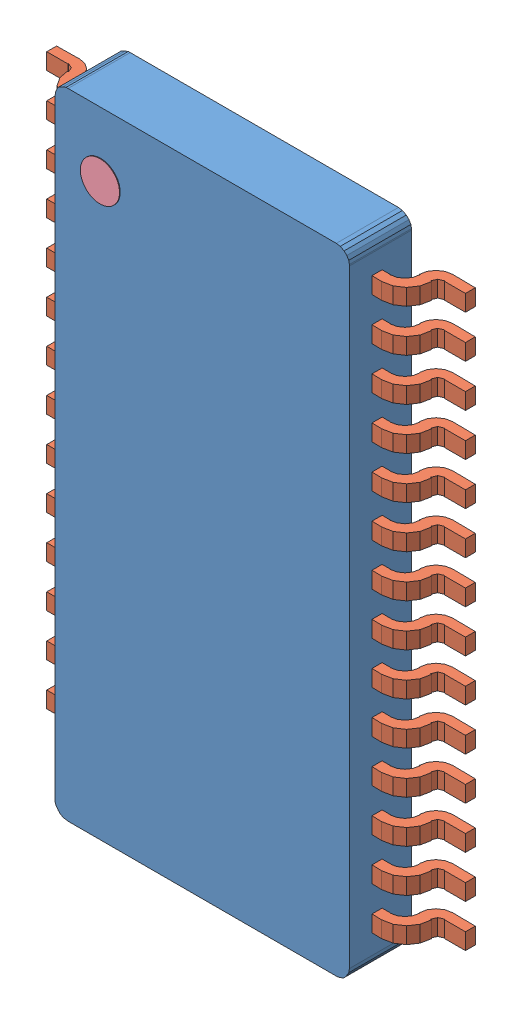
SolidWorks assembly User Library-TSSOP-28_P065, configuration Default. Lengths in mm.
Overall size (6.4 9.7 0.99).
146 component instances, 5 part files, 0 mates.
Components (placement in the parent):
- User Library-TSSOP-28_P065_Free-Models2-1: User Library-TSSOP-28_P065_Free-Models2 [Default] at origin size (6.4 9.7 0.99)
  - User Library-TSSOP-28_P065_455332561-1: User Library-TSSOP-28_P065_455332561 [Default] at (0 0 -0.4373) size (4.5 9.7 0.95)
    - User Library-TSSOP-28_P065_Extruded2-1: User Library-TSSOP-28_P065_Extruded2 [Default] at origin size (4.5 9.7 0.95)
  - User Library-TSSOP-28_P065_PINTSSOP-57-1: User Library-TSSOP-28_P065_PINTSSOP-57 [Default] at (2.1 0.4373 0.0127) x (-1 0 0) z (0 1 0) size (1.1 0.64 0.42)
    - User Library-TSSOP-28_P065_Free-Models3-1: User Library-TSSOP-28_P065_Free-Models3 [Default] at origin size (1.1 0.64 0.25)
      - User Library-TSSOP-28_P065_353885137-1: User Library-TSSOP-28_P065_353885137 [Default] at (-0.55 -0.1603 -0.2373) size (1.1 0.64 0.25)
        - User Library-TSSOP-28_P065_Extruded3-1: User Library-TSSOP-28_P065_Extruded3 [Default] at origin size (1.1 0.64 0.25)
    - User Library-TSSOP-28_P065_Board3-1: User Library-TSSOP-28_P065_Board3 [Default] at (0 0 -0.4039) size (0 0 0.42)
  - User Library-TSSOP-28_P065_PINTSSOP-57-2: User Library-TSSOP-28_P065_PINTSSOP-57 [Default] at (-2.1 0.8627 0.0127) x (1 0 0) z (0 -1 0) size (1.1 0.64 0.42)
    - User Library-TSSOP-28_P065_Free-Models3-1: User Library-TSSOP-28_P065_Free-Models3 [Default] at origin size (1.1 0.64 0.25)
      - User Library-TSSOP-28_P065_353885137-1: User Library-TSSOP-28_P065_353885137 [Default] at (-0.55 -0.1603 -0.2373) size (1.1 0.64 0.25)
        - User Library-TSSOP-28_P065_Extruded3-1: User Library-TSSOP-28_P065_Extruded3 [Default] at origin size (1.1 0.64 0.25)
    - User Library-TSSOP-28_P065_Board3-1: User Library-TSSOP-28_P065_Board3 [Default] at (0 0 -0.4039) size (0 0 0.42)
  - User Library-TSSOP-28_P065_PINTSSOP-57-3: User Library-TSSOP-28_P065_PINTSSOP-57 [Default] at (2.1 1.0873 0.0127) x (-1 0 0) z (0 1 0) size (1.1 0.64 0.42)
    - User Library-TSSOP-28_P065_Free-Models3-1: User Library-TSSOP-28_P065_Free-Models3 [Default] at origin size (1.1 0.64 0.25)
      - User Library-TSSOP-28_P065_353885137-1: User Library-TSSOP-28_P065_353885137 [Default] at (-0.55 -0.1603 -0.2373) size (1.1 0.64 0.25)
        - User Library-TSSOP-28_P065_Extruded3-1: User Library-TSSOP-28_P065_Extruded3 [Default] at origin size (1.1 0.64 0.25)
    - User Library-TSSOP-28_P065_Board3-1: User Library-TSSOP-28_P065_Board3 [Default] at (0 0 -0.4039) size (0 0 0.42)
  - User Library-TSSOP-28_P065_PINTSSOP-57-4: User Library-TSSOP-28_P065_PINTSSOP-57 [Default] at (-2.1 1.5127 0.0127) x (1 0 0) z (0 -1 0) size (1.1 0.64 0.42)
    - User Library-TSSOP-28_P065_Free-Models3-1: User Library-TSSOP-28_P065_Free-Models3 [Default] at origin size (1.1 0.64 0.25)
      - User Library-TSSOP-28_P065_353885137-1: User Library-TSSOP-28_P065_353885137 [Default] at (-0.55 -0.1603 -0.2373) size (1.1 0.64 0.25)
        - User Library-TSSOP-28_P065_Extruded3-1: User Library-TSSOP-28_P065_Extruded3 [Default] at origin size (1.1 0.64 0.25)
    - User Library-TSSOP-28_P065_Board3-1: User Library-TSSOP-28_P065_Board3 [Default] at (0 0 -0.4039) size (0 0 0.42)
  - User Library-TSSOP-28_P065_PINTSSOP-57-5: User Library-TSSOP-28_P065_PINTSSOP-57 [Default] at (2.1 1.7373 0.0127) x (-1 0 0) z (0 1 0) size (1.1 0.64 0.42)
    - User Library-TSSOP-28_P065_Free-Models3-1: User Library-TSSOP-28_P065_Free-Models3 [Default] at origin size (1.1 0.64 0.25)
      - User Library-TSSOP-28_P065_353885137-1: User Library-TSSOP-28_P065_353885137 [Default] at (-0.55 -0.1603 -0.2373) size (1.1 0.64 0.25)
        - User Library-TSSOP-28_P065_Extruded3-1: User Library-TSSOP-28_P065_Extruded3 [Default] at origin size (1.1 0.64 0.25)
    - User Library-TSSOP-28_P065_Board3-1: User Library-TSSOP-28_P065_Board3 [Default] at (0 0 -0.4039) size (0 0 0.42)
  - User Library-TSSOP-28_P065_PINTSSOP-57-6: User Library-TSSOP-28_P065_PINTSSOP-57 [Default] at (-2.1 2.1627 0.0127) x (1 0 0) z (0 -1 0) size (1.1 0.64 0.42)
    - User Library-TSSOP-28_P065_Free-Models3-1: User Library-TSSOP-28_P065_Free-Models3 [Default] at origin size (1.1 0.64 0.25)
      - User Library-TSSOP-28_P065_353885137-1: User Library-TSSOP-28_P065_353885137 [Default] at (-0.55 -0.1603 -0.2373) size (1.1 0.64 0.25)
        - User Library-TSSOP-28_P065_Extruded3-1: User Library-TSSOP-28_P065_Extruded3 [Default] at origin size (1.1 0.64 0.25)
    - User Library-TSSOP-28_P065_Board3-1: User Library-TSSOP-28_P065_Board3 [Default] at (0 0 -0.4039) size (0 0 0.42)
  - User Library-TSSOP-28_P065_PINTSSOP-57-7: User Library-TSSOP-28_P065_PINTSSOP-57 [Default] at (2.1 2.3873 0.0127) x (-1 0 0) z (0 1 0) size (1.1 0.64 0.42)
    - User Library-TSSOP-28_P065_Free-Models3-1: User Library-TSSOP-28_P065_Free-Models3 [Default] at origin size (1.1 0.64 0.25)
      - User Library-TSSOP-28_P065_353885137-1: User Library-TSSOP-28_P065_353885137 [Default] at (-0.55 -0.1603 -0.2373) size (1.1 0.64 0.25)
        - User Library-TSSOP-28_P065_Extruded3-1: User Library-TSSOP-28_P065_Extruded3 [Default] at origin size (1.1 0.64 0.25)
    - User Library-TSSOP-28_P065_Board3-1: User Library-TSSOP-28_P065_Board3 [Default] at (0 0 -0.4039) size (0 0 0.42)
  - User Library-TSSOP-28_P065_PINTSSOP-57-8: User Library-TSSOP-28_P065_PINTSSOP-57 [Default] at (-2.1 2.8127 0.0127) x (1 0 0) z (0 -1 0) size (1.1 0.64 0.42)
    - User Library-TSSOP-28_P065_Free-Models3-1: User Library-TSSOP-28_P065_Free-Models3 [Default] at origin size (1.1 0.64 0.25)
      - User Library-TSSOP-28_P065_353885137-1: User Library-TSSOP-28_P065_353885137 [Default] at (-0.55 -0.1603 -0.2373) size (1.1 0.64 0.25)
        - User Library-TSSOP-28_P065_Extruded3-1: User Library-TSSOP-28_P065_Extruded3 [Default] at origin size (1.1 0.64 0.25)
    - User Library-TSSOP-28_P065_Board3-1: User Library-TSSOP-28_P065_Board3 [Default] at (0 0 -0.4039) size (0 0 0.42)
  - User Library-TSSOP-28_P065_PINTSSOP-57-9: User Library-TSSOP-28_P065_PINTSSOP-57 [Default] at (2.1 3.0373 0.0127) x (-1 0 0) z (0 1 0) size (1.1 0.64 0.42)
    - User Library-TSSOP-28_P065_Free-Models3-1: User Library-TSSOP-28_P065_Free-Models3 [Default] at origin size (1.1 0.64 0.25)
      - User Library-TSSOP-28_P065_353885137-1: User Library-TSSOP-28_P065_353885137 [Default] at (-0.55 -0.1603 -0.2373) size (1.1 0.64 0.25)
        - User Library-TSSOP-28_P065_Extruded3-1: User Library-TSSOP-28_P065_Extruded3 [Default] at origin size (1.1 0.64 0.25)
    - User Library-TSSOP-28_P065_Board3-1: User Library-TSSOP-28_P065_Board3 [Default] at (0 0 -0.4039) size (0 0 0.42)
  - User Library-TSSOP-28_P065_PINTSSOP-57-10: User Library-TSSOP-28_P065_PINTSSOP-57 [Default] at (-2.1 3.4627 0.0127) x (1 0 0) z (0 -1 0) size (1.1 0.64 0.42)
    - User Library-TSSOP-28_P065_Free-Models3-1: User Library-TSSOP-28_P065_Free-Models3 [Default] at origin size (1.1 0.64 0.25)
      - User Library-TSSOP-28_P065_353885137-1: User Library-TSSOP-28_P065_353885137 [Default] at (-0.55 -0.1603 -0.2373) size (1.1 0.64 0.25)
        - User Library-TSSOP-28_P065_Extruded3-1: User Library-TSSOP-28_P065_Extruded3 [Default] at origin size (1.1 0.64 0.25)
    - User Library-TSSOP-28_P065_Board3-1: User Library-TSSOP-28_P065_Board3 [Default] at (0 0 -0.4039) size (0 0 0.42)
  - User Library-TSSOP-28_P065_PINTSSOP-57-11: User Library-TSSOP-28_P065_PINTSSOP-57 [Default] at (2.1 3.6873 0.0127) x (-1 0 0) z (0 1 0) size (1.1 0.64 0.42)
    - User Library-TSSOP-28_P065_Free-Models3-1: User Library-TSSOP-28_P065_Free-Models3 [Default] at origin size (1.1 0.64 0.25)
      - User Library-TSSOP-28_P065_353885137-1: User Library-TSSOP-28_P065_353885137 [Default] at (-0.55 -0.1603 -0.2373) size (1.1 0.64 0.25)
        - User Library-TSSOP-28_P065_Extruded3-1: User Library-TSSOP-28_P065_Extruded3 [Default] at origin size (1.1 0.64 0.25)
    - User Library-TSSOP-28_P065_Board3-1: User Library-TSSOP-28_P065_Board3 [Default] at (0 0 -0.4039) size (0 0 0.42)
  - User Library-TSSOP-28_P065_PINTSSOP-57-12: User Library-TSSOP-28_P065_PINTSSOP-57 [Default] at (-2.1 4.1127 0.0127) x (1 0 0) z (0 -1 0) size (1.1 0.64 0.42)
    - User Library-TSSOP-28_P065_Free-Models3-1: User Library-TSSOP-28_P065_Free-Models3 [Default] at origin size (1.1 0.64 0.25)
      - User Library-TSSOP-28_P065_353885137-1: User Library-TSSOP-28_P065_353885137 [Default] at (-0.55 -0.1603 -0.2373) size (1.1 0.64 0.25)
        - User Library-TSSOP-28_P065_Extruded3-1: User Library-TSSOP-28_P065_Extruded3 [Default] at origin size (1.1 0.64 0.25)
    - User Library-TSSOP-28_P065_Board3-1: User Library-TSSOP-28_P065_Board3 [Default] at (0 0 -0.4039) size (0 0 0.42)
  - User Library-TSSOP-28_P065_PINTSSOP-57-13: User Library-TSSOP-28_P065_PINTSSOP-57 [Default] at (2.1 4.3373 0.0127) x (-1 0 0) z (0 1 0) size (1.1 0.64 0.42)
    - User Library-TSSOP-28_P065_Free-Models3-1: User Library-TSSOP-28_P065_Free-Models3 [Default] at origin size (1.1 0.64 0.25)
      - User Library-TSSOP-28_P065_353885137-1: User Library-TSSOP-28_P065_353885137 [Default] at (-0.55 -0.1603 -0.2373) size (1.1 0.64 0.25)
        - User Library-TSSOP-28_P065_Extruded3-1: User Library-TSSOP-28_P065_Extruded3 [Default] at origin size (1.1 0.64 0.25)
    - User Library-TSSOP-28_P065_Board3-1: User Library-TSSOP-28_P065_Board3 [Default] at (0 0 -0.4039) size (0 0 0.42)
  - User Library-TSSOP-28_P065_PINTSSOP-57-14: User Library-TSSOP-28_P065_PINTSSOP-57 [Default] at (-2.1 -1.7373 0.0127) x (1 0 0) z (0 -1 0) size (1.1 0.64 0.42)
    - User Library-TSSOP-28_P065_Free-Models3-1: User Library-TSSOP-28_P065_Free-Models3 [Default] at origin size (1.1 0.64 0.25)
      - User Library-TSSOP-28_P065_353885137-1: User Library-TSSOP-28_P065_353885137 [Default] at (-0.55 -0.1603 -0.2373) size (1.1 0.64 0.25)
        - User Library-TSSOP-28_P065_Extruded3-1: User Library-TSSOP-28_P065_Extruded3 [Default] at origin size (1.1 0.64 0.25)
    - User Library-TSSOP-28_P065_Board3-1: User Library-TSSOP-28_P065_Board3 [Default] at (0 0 -0.4039) size (0 0 0.42)
  - User Library-TSSOP-28_P065_PINTSSOP-57-15: User Library-TSSOP-28_P065_PINTSSOP-57 [Default] at (2.1 -1.5127 0.0127) x (-1 0 0) z (0 1 0) size (1.1 0.64 0.42)
    - User Library-TSSOP-28_P065_Free-Models3-1: User Library-TSSOP-28_P065_Free-Models3 [Default] at origin size (1.1 0.64 0.25)
      - User Library-TSSOP-28_P065_353885137-1: User Library-TSSOP-28_P065_353885137 [Default] at (-0.55 -0.1603 -0.2373) size (1.1 0.64 0.25)
        - User Library-TSSOP-28_P065_Extruded3-1: User Library-TSSOP-28_P065_Extruded3 [Default] at origin size (1.1 0.64 0.25)
    - User Library-TSSOP-28_P065_Board3-1: User Library-TSSOP-28_P065_Board3 [Default] at (0 0 -0.4039) size (0 0 0.42)
  - User Library-TSSOP-28_P065_PINTSSOP-57-16: User Library-TSSOP-28_P065_PINTSSOP-57 [Default] at (-2.1 -1.0873 0.0127) x (1 0 0) z (0 -1 0) size (1.1 0.64 0.42)
    - User Library-TSSOP-28_P065_Free-Models3-1: User Library-TSSOP-28_P065_Free-Models3 [Default] at origin size (1.1 0.64 0.25)
      - User Library-TSSOP-28_P065_353885137-1: User Library-TSSOP-28_P065_353885137 [Default] at (-0.55 -0.1603 -0.2373) size (1.1 0.64 0.25)
        - User Library-TSSOP-28_P065_Extruded3-1: User Library-TSSOP-28_P065_Extruded3 [Default] at origin size (1.1 0.64 0.25)
    - User Library-TSSOP-28_P065_Board3-1: User Library-TSSOP-28_P065_Board3 [Default] at (0 0 -0.4039) size (0 0 0.42)
  - User Library-TSSOP-28_P065_PINTSSOP-57-17: User Library-TSSOP-28_P065_PINTSSOP-57 [Default] at (2.1 -0.8627 0.0127) x (-1 0 0) z (0 1 0) size (1.1 0.64 0.42)
    - User Library-TSSOP-28_P065_Free-Models3-1: User Library-TSSOP-28_P065_Free-Models3 [Default] at origin size (1.1 0.64 0.25)
      - User Library-TSSOP-28_P065_353885137-1: User Library-TSSOP-28_P065_353885137 [Default] at (-0.55 -0.1603 -0.2373) size (1.1 0.64 0.25)
        - User Library-TSSOP-28_P065_Extruded3-1: User Library-TSSOP-28_P065_Extruded3 [Default] at origin size (1.1 0.64 0.25)
    - User Library-TSSOP-28_P065_Board3-1: User Library-TSSOP-28_P065_Board3 [Default] at (0 0 -0.4039) size (0 0 0.42)
  - User Library-TSSOP-28_P065_PINTSSOP-57-18: User Library-TSSOP-28_P065_PINTSSOP-57 [Default] at (-2.1 -0.4373 0.0127) x (1 0 0) z (0 -1 0) size (1.1 0.64 0.42)
    - User Library-TSSOP-28_P065_Free-Models3-1: User Library-TSSOP-28_P065_Free-Models3 [Default] at origin size (1.1 0.64 0.25)
      - User Library-TSSOP-28_P065_353885137-1: User Library-TSSOP-28_P065_353885137 [Default] at (-0.55 -0.1603 -0.2373) size (1.1 0.64 0.25)
        - User Library-TSSOP-28_P065_Extruded3-1: User Library-TSSOP-28_P065_Extruded3 [Default] at origin size (1.1 0.64 0.25)
    - User Library-TSSOP-28_P065_Board3-1: User Library-TSSOP-28_P065_Board3 [Default] at (0 0 -0.4039) size (0 0 0.42)
  - User Library-TSSOP-28_P065_PINTSSOP-57-19: User Library-TSSOP-28_P065_PINTSSOP-57 [Default] at (2.1 -0.2127 0.0127) x (-1 0 0) z (0 1 0) size (1.1 0.64 0.42)
    - User Library-TSSOP-28_P065_Free-Models3-1: User Library-TSSOP-28_P065_Free-Models3 [Default] at origin size (1.1 0.64 0.25)
      - User Library-TSSOP-28_P065_353885137-1: User Library-TSSOP-28_P065_353885137 [Default] at (-0.55 -0.1603 -0.2373) size (1.1 0.64 0.25)
        - User Library-TSSOP-28_P065_Extruded3-1: User Library-TSSOP-28_P065_Extruded3 [Default] at origin size (1.1 0.64 0.25)
    - User Library-TSSOP-28_P065_Board3-1: User Library-TSSOP-28_P065_Board3 [Default] at (0 0 -0.4039) size (0 0 0.42)
  - User Library-TSSOP-28_P065_PINTSSOP-57-20: User Library-TSSOP-28_P065_PINTSSOP-57 [Default] at (-2.1 0.2127 0.0127) x (1 0 0) z (0 -1 0) size (1.1 0.64 0.42)
    - User Library-TSSOP-28_P065_Free-Models3-1: User Library-TSSOP-28_P065_Free-Models3 [Default] at origin size (1.1 0.64 0.25)
      - User Library-TSSOP-28_P065_353885137-1: User Library-TSSOP-28_P065_353885137 [Default] at (-0.55 -0.1603 -0.2373) size (1.1 0.64 0.25)
        - User Library-TSSOP-28_P065_Extruded3-1: User Library-TSSOP-28_P065_Extruded3 [Default] at origin size (1.1 0.64 0.25)
    - User Library-TSSOP-28_P065_Board3-1: User Library-TSSOP-28_P065_Board3 [Default] at (0 0 -0.4039) size (0 0 0.42)
  - User Library-TSSOP-28_P065_PINTSSOP-57-21: User Library-TSSOP-28_P065_PINTSSOP-57 [Default] at (-2.1 -4.3373 0.0127) x (1 0 0) z (0 -1 0) size (1.1 0.64 0.42)
    - User Library-TSSOP-28_P065_Free-Models3-1: User Library-TSSOP-28_P065_Free-Models3 [Default] at origin size (1.1 0.64 0.25)
      - User Library-TSSOP-28_P065_353885137-1: User Library-TSSOP-28_P065_353885137 [Default] at (-0.55 -0.1603 -0.2373) size (1.1 0.64 0.25)
        - User Library-TSSOP-28_P065_Extruded3-1: User Library-TSSOP-28_P065_Extruded3 [Default] at origin size (1.1 0.64 0.25)
    - User Library-TSSOP-28_P065_Board3-1: User Library-TSSOP-28_P065_Board3 [Default] at (0 0 -0.4039) size (0 0 0.42)
  - User Library-TSSOP-28_P065_PINTSSOP-57-22: User Library-TSSOP-28_P065_PINTSSOP-57 [Default] at (2.1 -4.1127 0.0127) x (-1 0 0) z (0 1 0) size (1.1 0.64 0.42)
    - User Library-TSSOP-28_P065_Free-Models3-1: User Library-TSSOP-28_P065_Free-Models3 [Default] at origin size (1.1 0.64 0.25)
      - User Library-TSSOP-28_P065_353885137-1: User Library-TSSOP-28_P065_353885137 [Default] at (-0.55 -0.1603 -0.2373) size (1.1 0.64 0.25)
        - User Library-TSSOP-28_P065_Extruded3-1: User Library-TSSOP-28_P065_Extruded3 [Default] at origin size (1.1 0.64 0.25)
    - User Library-TSSOP-28_P065_Board3-1: User Library-TSSOP-28_P065_Board3 [Default] at (0 0 -0.4039) size (0 0 0.42)
  - User Library-TSSOP-28_P065_PINTSSOP-57-23: User Library-TSSOP-28_P065_PINTSSOP-57 [Default] at (-2.1 -3.6873 0.0127) x (1 0 0) z (0 -1 0) size (1.1 0.64 0.42)
    - User Library-TSSOP-28_P065_Free-Models3-1: User Library-TSSOP-28_P065_Free-Models3 [Default] at origin size (1.1 0.64 0.25)
      - User Library-TSSOP-28_P065_353885137-1: User Library-TSSOP-28_P065_353885137 [Default] at (-0.55 -0.1603 -0.2373) size (1.1 0.64 0.25)
        - User Library-TSSOP-28_P065_Extruded3-1: User Library-TSSOP-28_P065_Extruded3 [Default] at origin size (1.1 0.64 0.25)
    - User Library-TSSOP-28_P065_Board3-1: User Library-TSSOP-28_P065_Board3 [Default] at (0 0 -0.4039) size (0 0 0.42)
  - User Library-TSSOP-28_P065_PINTSSOP-57-24: User Library-TSSOP-28_P065_PINTSSOP-57 [Default] at (2.1 -3.4627 0.0127) x (-1 0 0) z (0 1 0) size (1.1 0.64 0.42)
    - User Library-TSSOP-28_P065_Free-Models3-1: User Library-TSSOP-28_P065_Free-Models3 [Default] at origin size (1.1 0.64 0.25)
      - User Library-TSSOP-28_P065_353885137-1: User Library-TSSOP-28_P065_353885137 [Default] at (-0.55 -0.1603 -0.2373) size (1.1 0.64 0.25)
        - User Library-TSSOP-28_P065_Extruded3-1: User Library-TSSOP-28_P065_Extruded3 [Default] at origin size (1.1 0.64 0.25)
    - User Library-TSSOP-28_P065_Board3-1: User Library-TSSOP-28_P065_Board3 [Default] at (0 0 -0.4039) size (0 0 0.42)
  - User Library-TSSOP-28_P065_PINTSSOP-57-25: User Library-TSSOP-28_P065_PINTSSOP-57 [Default] at (-2.1 -3.0373 0.0127) x (1 0 0) z (0 -1 0) size (1.1 0.64 0.42)
    - User Library-TSSOP-28_P065_Free-Models3-1: User Library-TSSOP-28_P065_Free-Models3 [Default] at origin size (1.1 0.64 0.25)
      - User Library-TSSOP-28_P065_353885137-1: User Library-TSSOP-28_P065_353885137 [Default] at (-0.55 -0.1603 -0.2373) size (1.1 0.64 0.25)
        - User Library-TSSOP-28_P065_Extruded3-1: User Library-TSSOP-28_P065_Extruded3 [Default] at origin size (1.1 0.64 0.25)
    - User Library-TSSOP-28_P065_Board3-1: User Library-TSSOP-28_P065_Board3 [Default] at (0 0 -0.4039) size (0 0 0.42)
  - User Library-TSSOP-28_P065_PINTSSOP-57-26: User Library-TSSOP-28_P065_PINTSSOP-57 [Default] at (2.1 -2.8127 0.0127) x (-1 0 0) z (0 1 0) size (1.1 0.64 0.42)
    - User Library-TSSOP-28_P065_Free-Models3-1: User Library-TSSOP-28_P065_Free-Models3 [Default] at origin size (1.1 0.64 0.25)
      - User Library-TSSOP-28_P065_353885137-1: User Library-TSSOP-28_P065_353885137 [Default] at (-0.55 -0.1603 -0.2373) size (1.1 0.64 0.25)
        - User Library-TSSOP-28_P065_Extruded3-1: User Library-TSSOP-28_P065_Extruded3 [Default] at origin size (1.1 0.64 0.25)
    - User Library-TSSOP-28_P065_Board3-1: User Library-TSSOP-28_P065_Board3 [Default] at (0 0 -0.4039) size (0 0 0.42)
  - User Library-TSSOP-28_P065_PINTSSOP-57-27: User Library-TSSOP-28_P065_PINTSSOP-57 [Default] at (-2.1 -2.3873 0.0127) x (1 0 0) z (0 -1 0) size (1.1 0.64 0.42)
    - User Library-TSSOP-28_P065_Free-Models3-1: User Library-TSSOP-28_P065_Free-Models3 [Default] at origin size (1.1 0.64 0.25)
      - User Library-TSSOP-28_P065_353885137-1: User Library-TSSOP-28_P065_353885137 [Default] at (-0.55 -0.1603 -0.2373) size (1.1 0.64 0.25)
        - User Library-TSSOP-28_P065_Extruded3-1: User Library-TSSOP-28_P065_Extruded3 [Default] at origin size (1.1 0.64 0.25)
    - User Library-TSSOP-28_P065_Board3-1: User Library-TSSOP-28_P065_Board3 [Default] at (0 0 -0.4039) size (0 0 0.42)
  - User Library-TSSOP-28_P065_PINTSSOP-57-28: User Library-TSSOP-28_P065_PINTSSOP-57 [Default] at (2.1 -2.1627 0.0127) x (-1 0 0) z (0 1 0) size (1.1 0.64 0.42)
    - User Library-TSSOP-28_P065_Free-Models3-1: User Library-TSSOP-28_P065_Free-Models3 [Default] at origin size (1.1 0.64 0.25)
      - User Library-TSSOP-28_P065_353885137-1: User Library-TSSOP-28_P065_353885137 [Default] at (-0.55 -0.1603 -0.2373) size (1.1 0.64 0.25)
        - User Library-TSSOP-28_P065_Extruded3-1: User Library-TSSOP-28_P065_Extruded3 [Default] at origin size (1.1 0.64 0.25)
    - User Library-TSSOP-28_P065_Board3-1: User Library-TSSOP-28_P065_Board3 [Default] at (0 0 -0.4039) size (0 0 0.42)
  - User Library-TSSOP-28_P065_455099953-1: User Library-TSSOP-28_P065_455099953 [Default] at (-1.5524 3.875 0.5127) size (0.6 0.6 0.01)
    - User Library-TSSOP-28_P065_Cylinder1-1: User Library-TSSOP-28_P065_Cylinder1 [Default] at origin size (0.6 0.6 0.01)
- User Library-TSSOP-28_P065_Board2-1: User Library-TSSOP-28_P065_Board2 [Default] at (0 0 -0.0938) size (0.01 0.01 0.11)
